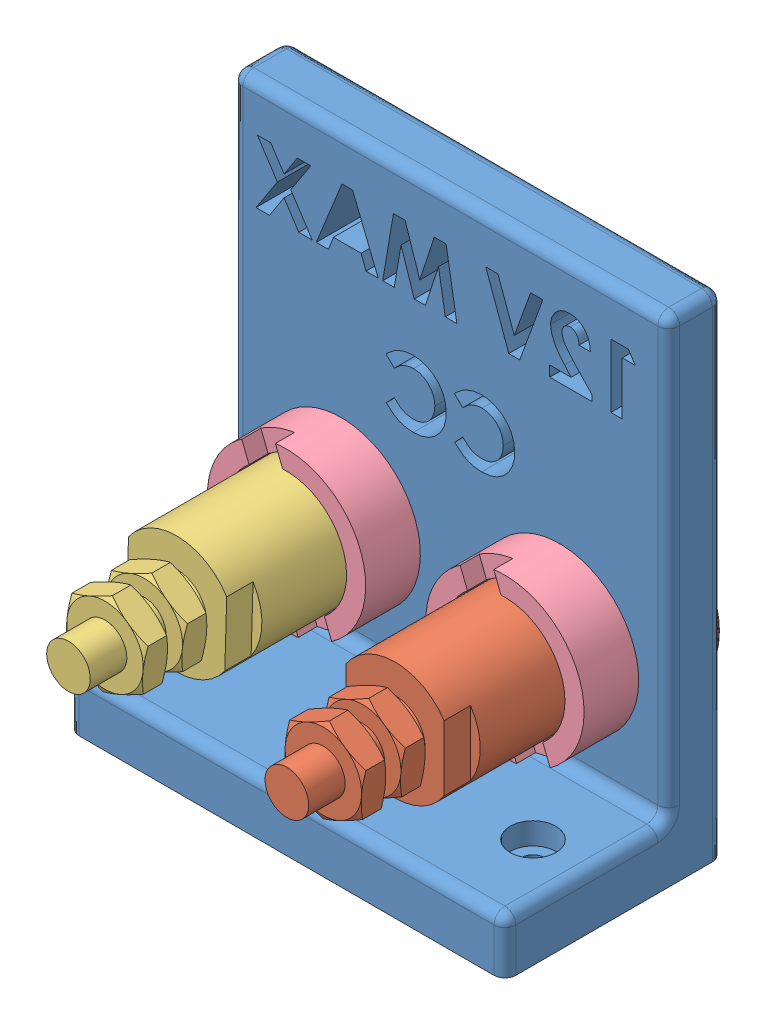
SolidWorks assembly alimentation, configuration Défaut. Lengths in mm.
Overall size (40 45 32.77).
5 component instances, 4 part files, 8 mates.
Components (placement in the parent):
- alimentation_support-1: alimentation_support [Défaut] at (-10.5748 2.0727 30) size (40 45 20)
- Douille banane noir-1: Douille banane noir [Default] at (-0.8911 1.5817 37.6675) x (1 0 0) z (0 1 0) size (14.4 32.77 14.4)
- Douille banane rouge-1: Douille banane rouge [Default] at (-20.9056 1.5913 37.6675) x (0.999557 -0.02976 0) z (0.02976 0.999557 0) size (14.4 32.77 14.4)
- Douille banane ecrou-1: Douille banane ecrou [Default] at (-20.4707 2.6475 39.6675) x (-0.923728 -0.383049 0) z (0.383049 -0.923728 0) size (14.5 5 14.5)
- Douille banane ecrou-2: Douille banane ecrou [Default] at (-0.4707 2.6475 39.6675) x (-0.923728 -0.383049 0) z (0.383049 -0.923728 0) size (14.5 5 14.5)
Mates (geometry in assembly coordinates):
- Coaxiale1: concentric anti-aligned: cylinder of alimentation_support-1 through (-20.5748 2.0727 35) axis (0 0 -1) radius 6.1; cylinder of Fiche banane rouge-1 through (-20.5748 2.0727 30) axis (0 0 1) radius 5.4
- Coaxiale2: concentric anti-aligned: cylinder of alimentation_support-1 through (-0.5748 2.0727 35) axis (0 0 -1) radius 6.1; cylinder of Fiche banane noir-1 through (-0.5748 2.0727 30) axis (0 0 1) radius 5.4
- Coïncidente1: coincident anti-aligned: plane of alimentation_support-1 through (-10.5748 2.0727 30) normal (0 0 -1); plane of Fiche banane noir-1 through (-0.5748 2.0727 30) normal (0 0 1)
- Coïncidente2: coincident anti-aligned: plane of alimentation_support-1 through (-10.5748 2.0727 30) normal (0 0 -1); plane of Fiche banane rouge-1 through (-20.5748 2.0727 30) normal (0 0 1)
- Coaxiale3: concentric aligned: cylinder of Fiche banane noir-1 through (-0.5748 2.0727 30) axis (0 0 1) radius 5.4; cylinder of Fiche banane ecrou-2 through (-0.5748 2.0727 35) axis (0 0 1) radius 5.5
- Coaxiale4: concentric aligned: cylinder of Fiche banane rouge-1 through (-20.5748 2.0727 30) axis (0 0 1) radius 5.4; cylinder of Fiche banane ecrou-1 through (-20.5748 2.0727 35) axis (0 0 1) radius 5.5
- Coïncidente3: coincident anti-aligned: plane of alimentation_support-1 through (-10.5748 2.0727 35) normal (0 0 1); plane of Fiche banane ecrou-2 through (-0.5748 2.0727 35) normal (0 0 -1)
- Coïncidente4: coincident anti-aligned: plane of alimentation_support-1 through (-10.5748 2.0727 35) normal (0 0 1); plane of Fiche banane ecrou-1 through (-20.5748 2.0727 35) normal (0 0 -1)
